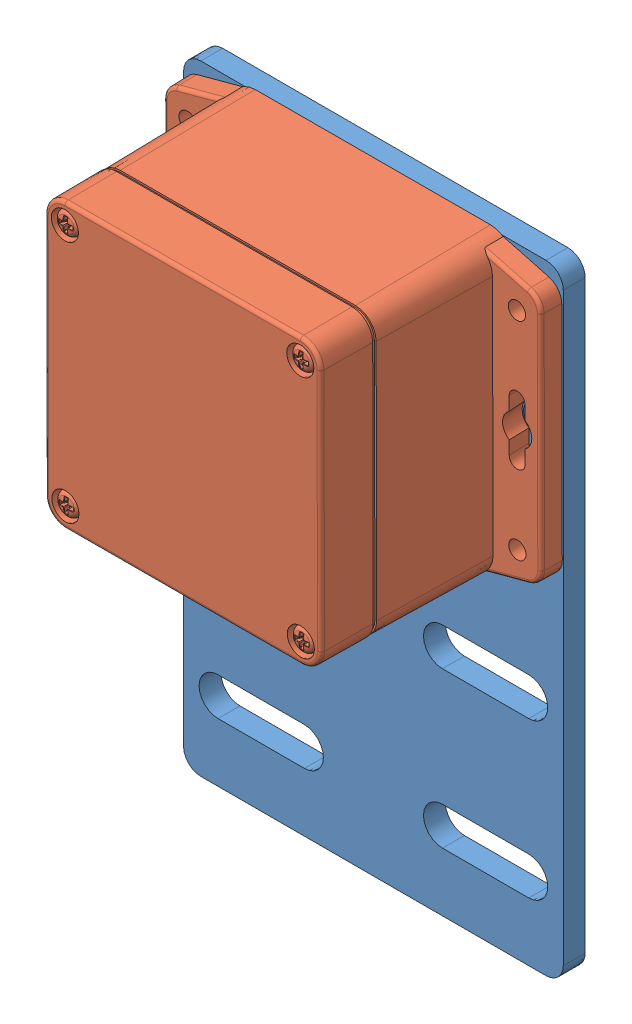
SolidWorks assembly Assem4, configuration Default. Lengths in mm.
Overall size (110 180.38 61.48).
2 component instances, 2 part files, 5 mates.
Components (placement in the parent):
- PipeMount-1: PipeMount [Default] at (-29.6396 120.9255 143.2716) size (110 179.46 6.35)
- W_-31F1-1: W_-31F1 [Default] at (25.2913 162.033 188.7486) x (0.002202 -0.999998 0) z (-0.999998 -0.002202 0) size (83.37 56.28 109.4)
Mates (geometry in assembly coordinates):
- Concentric1: concentric aligned: cylinder of PipeMount-1 through (73.0616 191.9229 143.2706) axis (0 0 1) radius 2.5019; cone of W_-31F1-1 through (73.0616 191.9229 149.6216) axis (0 0 1)
- Parallel7: parallel: plane of PipeMount-1 through (-29.6396 120.9255 149.6216) normal (-1 0 0); plane of W_-31F1-1
- Parallel9: parallel: plane of PipeMount-1 through (-29.6396 202.9255 149.6216) normal (0 1 0); plane of W_-31F1-1
- Concentric8: concentric aligned: circle of PipeMount-1; circle of W_-31F1-1
- Coincident9: coincident anti-aligned: plane of PipeMount-1 through (-29.6396 120.9255 149.6216) normal (0 0 1); plane of W_-31F1-1 through (59.2826 197.108 149.6216) normal (0 0 -1)
